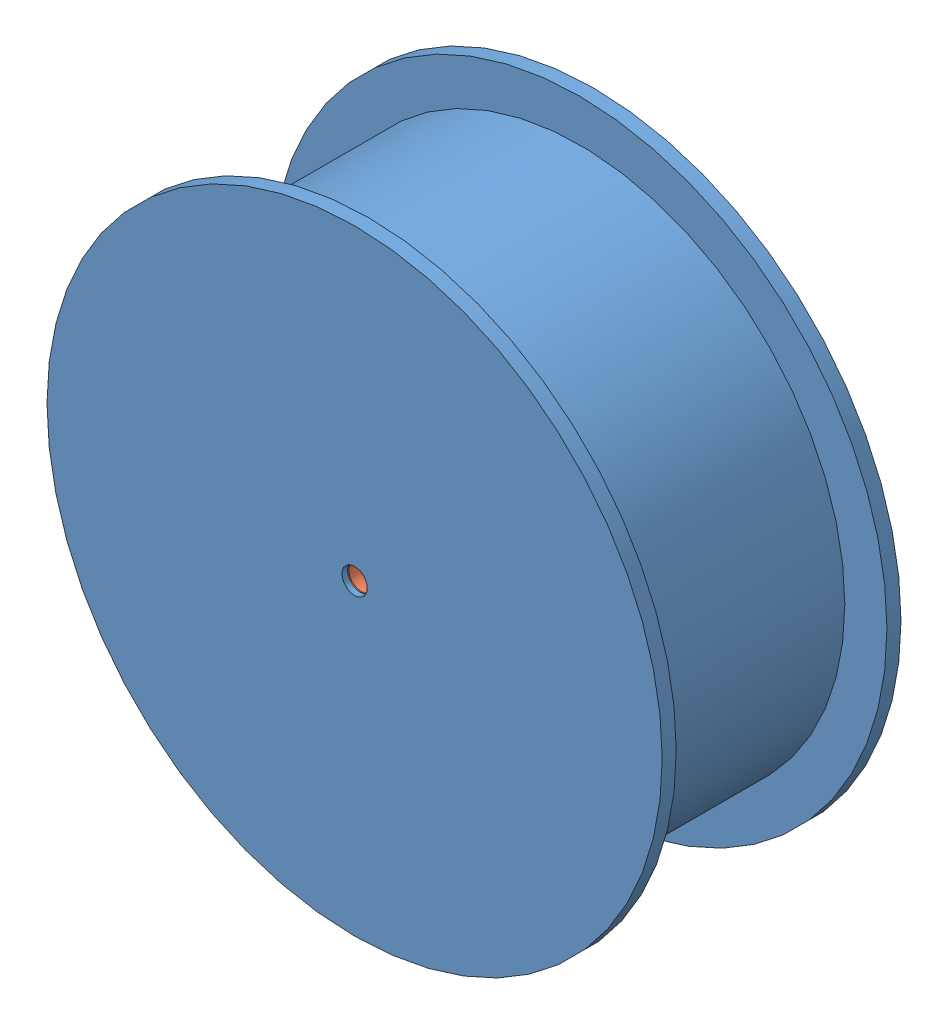
SolidWorks assembly Hub_bearing_assembly, configuration Default. Lengths in mm.
Overall size (219 219 85).
2 component instances, 2 part files, 2 mates.
Components (placement in the parent):
- Hub-1: Hub [Default] at origin size (219 219 85)
- Outer_shaft_bearing-1: Outer_shaft_bearing [5972K231] at (0 0 18.4118) x (0.627924 0.778275 0) z (0 0 1) size (26 26 8)
Mates (geometry in assembly coordinates):
- Coincident1: coincident anti-aligned: plane of Hub-1 through (0 0 22.4118) normal (0 0 -1); plane of Outer_shaft_bearing-1 through (-6.1941 4.9975 22.4118) normal (0 0 1)
- Concentric2: concentric aligned: cylinder of Hub-1 through (0 0 -60.5882) axis (0 0 1) radius 4.5; cylinder of Outer_shaft_bearing-1 through (0 0 22.4118) axis (0 0 1) radius 4.5
